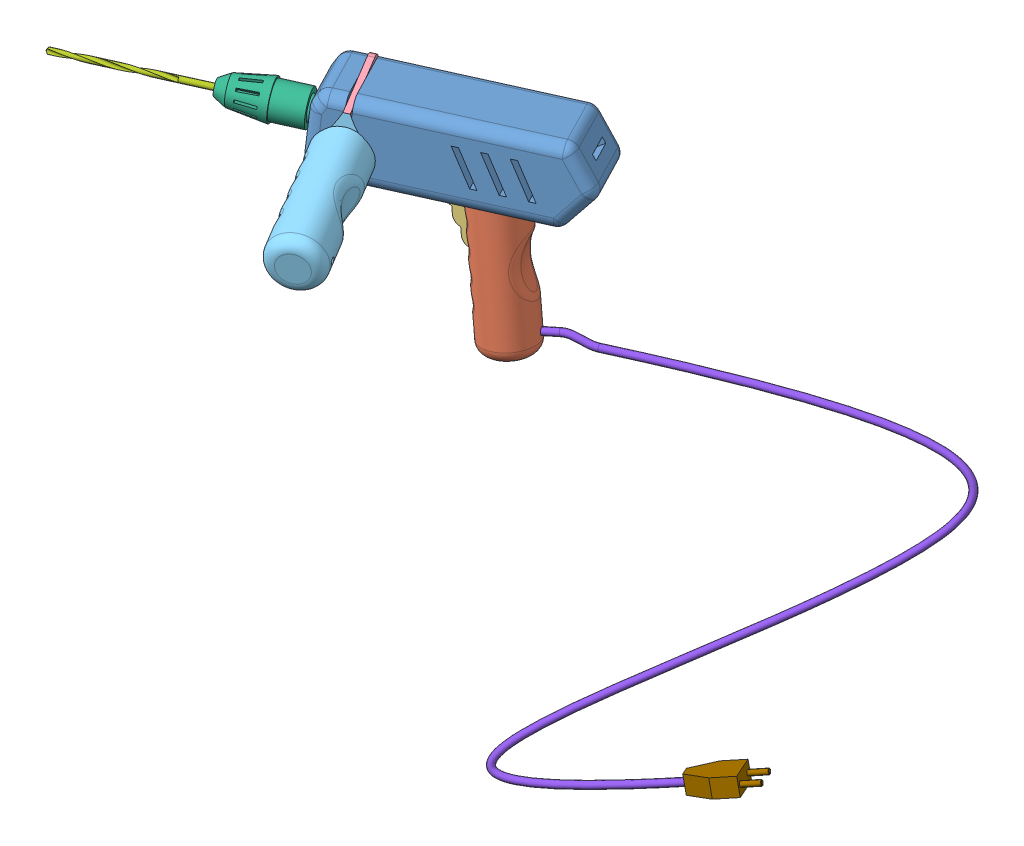
SolidWorks assembly PowerDrillI1, configuration Default. Lengths in mm.
Overall size (631.22 472.66 354.1).
9 component instances, 9 part files, 19 mates.
Components (placement in the parent):
- body-2: body [Default] at (72.9871 127.7914 136.1233) x (0.865483 -0.072857 -0.495613) z (0.500931 0.120407 0.857071) size (197.69 64.52 70)
- handle-2: handle [Default] at (119.1866 101.9555 154.307) x (0.852815 0.10017 -0.512517) z (0.147563 -0.987658 0.052507) size (45.68 45 121.93)
- triger-1: triger [Default] at (107.8799 58.4933 166.3019) x (-0.500931 -0.120407 -0.857071) z (0.852815 0.10017 -0.512517) size (15 44.12 15)
- support-1: support [Default] at (17.9285 107.1091 172.9127) x (0.865483 -0.072857 -0.495613) z (0.100809 0.994458 0.029852) size (5 70 64.5)
- handle - support-1: handle - support [Default] at (54.251 134.0558 232.912) x (0.865483 -0.072857 -0.495613) z (0.490691 -0.075798 0.868031) size (45.68 64.5 125)
- chalck-1: chalck [Default] at (20.762 131.7872 199.9852) x (0.865483 -0.072857 -0.495613) z (0.322103 -0.676786 0.661975) size (88 32.58 32.58)
- drillbit-1: drillbit [Default] at (-148.4766 151.9997 302.9979) x (-0.099286 0.944791 -0.312269) z (-0.491001 -0.319471 -0.810467) size (9.13 120.25 9.17)
- wire-2: wire [Default] at (134.5331 -0.7609 159.7677) x (-0.462848 -0.309487 -0.830656) z (-0.852815 -0.10017 0.512517) size (6 313.64 335.27)
- plug-1: plug [Default] at (331.9313 -259.418 139.5276) x (-0.49471 -0.214781 -0.842099) z (0.292288 -0.953652 0.071522) size (30 54.34 15)
Mates (geometry in assembly coordinates):
- Concentric3: concentric anti-aligned: cylinder of body-2 through (116.0675 122.8317 153.1972) axis (0.147563 -0.987658 0.052507) radius 7.3861; cylinder of handle-2 through (122.5805 79.2394 155.5147) axis (-0.147563 0.987658 -0.052507) radius 7.5
- Coincident1: coincident anti-aligned: plane of body-2 through (180.6752 98.5001 158.9715) normal (-0.002768 -0.990047 0.140707); plane of handle-2 through (137.6144 92.8772 118.5597) normal (0.002768 0.990047 -0.140707)
- Parallel2: parallel aligned: plane of body-2 through (72.9871 127.7914 136.1233) normal (-0.500931 -0.120407 -0.857071); plane of triger-1 through (104.1229 57.5902 159.8738) normal (-0.500931 -0.120407 -0.857071)
- Coincident4: coincident anti-aligned: plane of body-2 through (180.6752 98.5001 158.9715) normal (-0.002768 -0.990047 0.140707); plane of triger-1 through (92.6905 102.9804 188.7647) normal (0.002768 0.990047 -0.140707)
- Width1: width aligned: plane of body-2 through (72.9871 127.7914 136.1233) normal (-0.500931 -0.120407 -0.857071); plane of body-2 through (108.0523 136.2199 196.1183) normal (0.500931 0.120407 0.857071); plane of triger-1 through (104.1229 57.5902 159.8738) normal (-0.500931 -0.120407 -0.857071); plane of triger-1 through (111.6369 59.3963 172.7299) normal (0.500931 0.120407 0.857071)
- Distance2: distance = 90 mm: line of triger-1 through (84.8207 99.6598 165.2452) axis (0.500931 0.120407 0.857071); plane of body-2 through (28.2512 123.612 244.5309) normal (-0.865483 0.072857 0.495613)
- Coincident13: coincident aligned: line of handle - support-1 through (46.3828 102.5456 228.8482) axis (0.865483 -0.072857 -0.495613); line of support-1 through (46.3828 102.5456 228.8482) axis (0.865483 -0.072857 -0.495613)
- Coincident14: coincident aligned: line of support-1 through (52.885 166.6882 230.7736) axis (0.865483 -0.072857 -0.495613); line of handle - support-1 through (52.885 166.6882 230.7736) axis (0.865483 -0.072857 -0.495613)
- Concentric6: concentric aligned: cylinder of body-2 through (36.7367 136.4083 196.9368) axis (-0.865483 0.072857 0.495613) radius 10; cylinder of chalck-1 through (-27.309 141.7997 233.6121) axis (-0.865483 0.072857 0.495613) radius 10
- Distance3: distance = 5 mm anti-aligned: plane of chalck-1 through (10.2813 146.284 219.906) normal (0.865483 -0.072857 -0.495613); plane of body-2 through (28.2512 123.612 244.5309) normal (-0.865483 0.072857 0.495613)
- Concentric7: concentric anti-aligned: cylinder of chalck-1 through (-47.2151 143.4755 245.0112) axis (0.865483 -0.072857 -0.495613) radius 2.5; cylinder of drillbit-1 through (-44.6187 143.2569 243.5244) axis (-0.865483 0.072857 0.495613) radius 2.5
- Distance5: distance = 20 mm anti-aligned: plane of chalck-1 through (-25.314 145.6091 236.536) normal (-0.865483 0.072857 0.495613); plane of drillbit-1 through (-44.6187 143.2569 243.5244) normal (0.865483 -0.072857 -0.495613)
- Concentric11: concentric anti-aligned: cylinder of handle-2 through (228.3427 10.2578 103.3909) axis (-0.852815 -0.10017 0.512517) radius 3; cylinder of wire-2 through (134.5331 -0.7609 159.7677) axis (0.852815 0.10017 -0.512517) radius 3
- Coincident25: coincident anti-aligned: circle of handle-2; circle of wire-2
- Distance7: distance = 0 mm anti-aligned: plane of support-1 through (22.864 171.6298 167.5334) normal (0.865483 -0.072857 -0.495613); plane of body-2 through (36.7367 136.4083 196.9368) normal (-0.865483 0.072857 0.495613)
- Concentric14: concentric anti-aligned: cylinder of body-2 through (32.4093 136.7726 199.4149) axis (0.865483 -0.072857 -0.495613) radius 21.9509; cylinder of support-1 through (41.0641 136.044 194.4588) axis (-0.865483 0.072857 0.495613) radius 21.9509
- Coincident26: coincident aligned: circle of wire-2; circle of plug-1
- Lock1: lock: unknown of wire-2; unknown of plug-1
- Coincident28: coincident: plane of support-1 through (52.885 166.6882 230.7736) normal (-0.865483 0.072857 0.495613); line of handle - support-1 through (46.3828 102.5456 228.8482) axis (0.100809 0.994458 0.029852)
